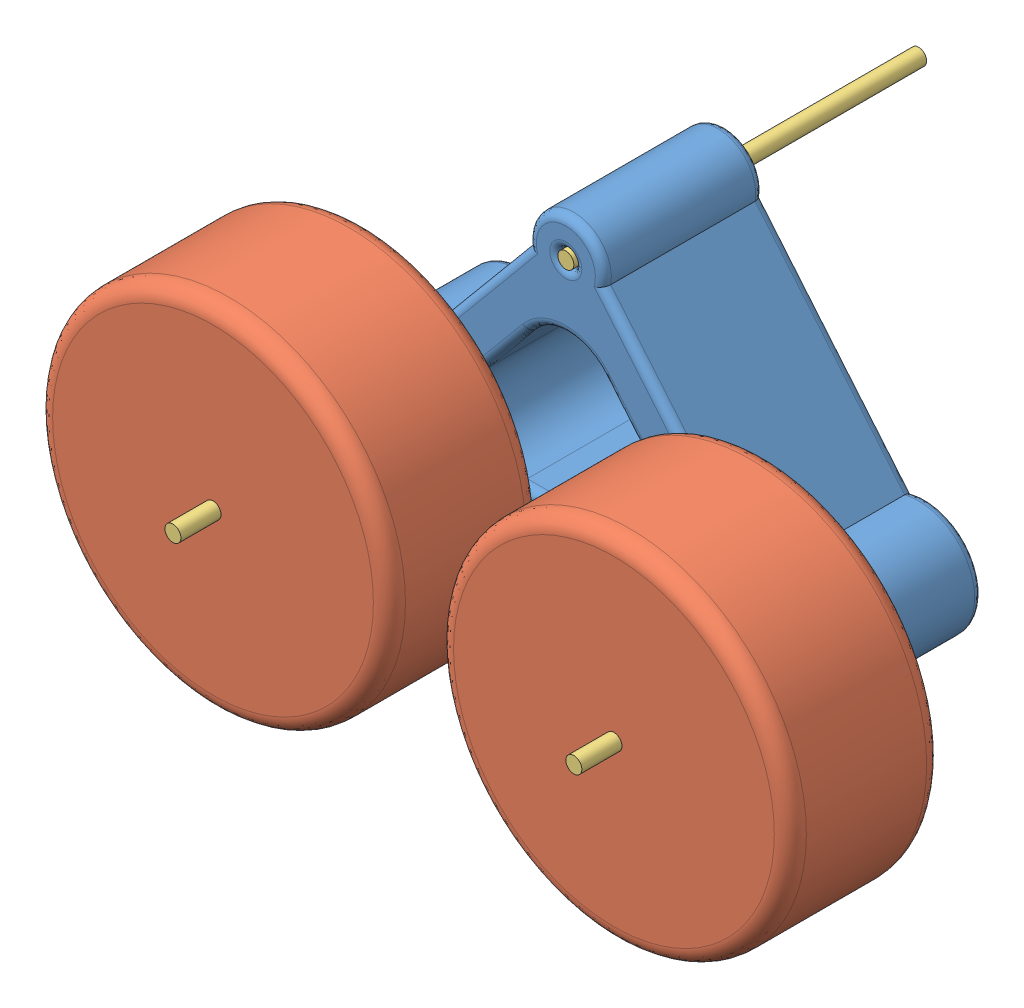
SolidWorks assembly assemblage roue, configuration Défaut. Lengths in mm.
Overall size (47 28.34 34).
6 component instances, 3 part files, 10 mates.
Components (placement in the parent):
- suspension-1: suspension [Default] at origin size (32 20.84 10.07)
- roue-1: roue [Default] at (-12.5 0 5) size (22 22 9.5)
- roue-2: roue [Default] at (12.5 0 5) size (22 22 9.5)
- tige roue-1: tige roue [Default] at (-12.5 0 -5) size (1 1 22)
- tige roue-2: tige roue [Default] at (0 15 -17) size (1 1 22)
- tige roue-3: tige roue [Default] at (12.5 0 -5) x (0.994836 0.1015 0) z (0 0 1) size (1 1 22)
Mates (geometry in assembly coordinates):
- Coaxiale1: concentric aligned: cylinder of suspension-1 through (-12.5 0 5) axis (0 0 -1) radius 0.5; cylinder of tige roue-1 through (-12.5 0 17) axis (0 0 -1) radius 0.5
- Coaxiale2: concentric: cylinder of suspension-1 through (0 15 5) axis (0 0 -1) radius 0.5; cylinder of tige roue-2 through (0 15 5) axis (0 0 -1) radius 0.5
- Coaxiale3: concentric aligned: cylinder of suspension-1 through (12.5 0 5) axis (0 0 -1) radius 0.5; cylinder of tige roue-3 through (12.5 0 17) axis (0 0 -1) radius 0.5
- Coïncidente1: coincident aligned: plane of suspension-1 through (12.5 0 5) normal (0 0 1); plane of tige roue-2 through (0 15 5) normal (0 0 1)
- Coïncidente2: coincident aligned: plane of suspension-1 through (12.5 0 -5) normal (0 0 -1); plane of tige roue-1 through (-12.5 0 -5) normal (0 0 -1)
- Coïncidente3: coincident aligned: plane of suspension-1 through (12.5 0 -5) normal (0 0 -1); plane of tige roue-3 through (12.5 0 -5) normal (0 0 -1)
- Coïncidente4: coincident anti-aligned: plane of suspension-1 through (12.5 0 5) normal (0 0 1); plane of roue-1 through (-12.5 0 5) normal (0 0 -1)
- Coïncidente5: coincident anti-aligned: plane of suspension-1 through (12.5 0 5) normal (0 0 1); plane of roue-2 through (12.5 0 5) normal (0 0 -1)
- Coaxiale5: concentric aligned: cylinder of roue-2 through (12.5 0 14.5) axis (0 0 -1) radius 0.5; cylinder of tige roue-3 through (12.5 0 17) axis (0 0 -1) radius 0.5
- Coaxiale6: concentric aligned: cylinder of roue-1 through (-12.5 0 14.5) axis (0 0 -1) radius 0.5; cylinder of tige roue-1 through (-12.5 0 17) axis (0 0 -1) radius 0.5
